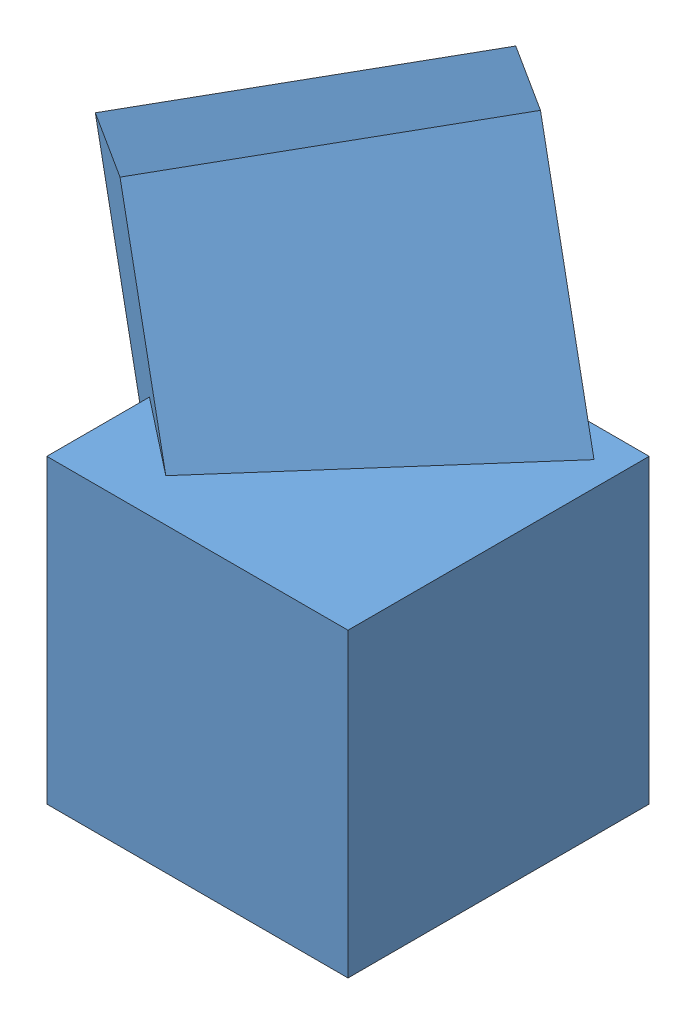
SolidWorks assembly test, configuration Default. Lengths in mm.
Overall size (17.16 17.46 16.58).
2 component instances, 1 part files, 0 mates.
Components (placement in the parent):
- test-1: test [Default] at (-1.9074 -0.7578 13.6769) size (10 10 10)
- test-2: test [Default] at (1.7888 6.7389 12.8266) x (0.614298 0.108339 -0.781602) z (0.672434 0.446417 0.590376) size (10 10 10)
